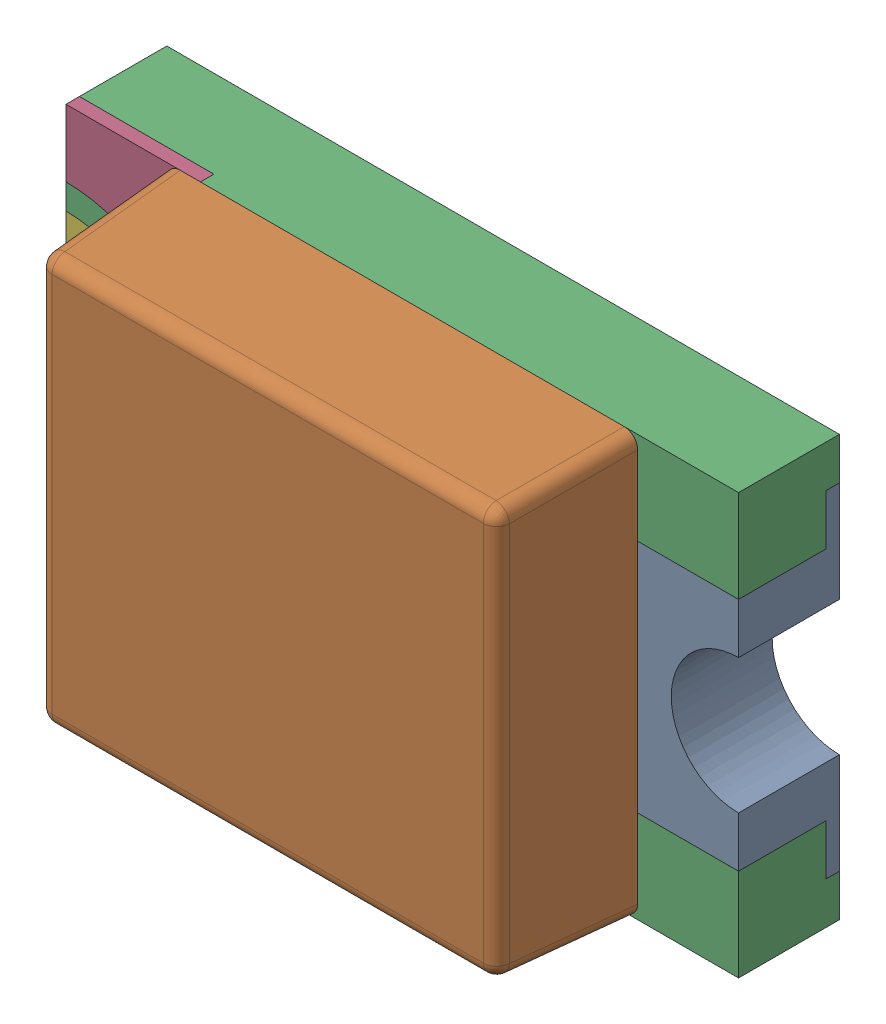
SolidWorks assembly D9, configuration Standard. Lengths in mm.
Overall size (2 1.25 0.7).
7 component instances, 5 part files, 0 mates.
Components (placement in the parent):
- WL-SMCW_0805_LED-1: WL-SMCW_0805_LED [Standard] at (12.1103 16.5697 -0.02) x (1 0 0) z (0 0 1) size (2 1.25 0.7)
  - base-1: base [Standard] at (0.8 0 0) x (-1 0 0) z (0 0 1) size (0.4 1 0.3)
  - cover-1: cover [Standard] at (0 0 0.3) size (1.4 1.25 0.4)
  - housing_3-1: housing_3 [Standard] at origin size (2 1.25 0.3)
  - marking-1: marking [Standard] at (-0.8 0.525 0.26) size (0.4 0.48 0.04)
  - marking-2: marking [Standard] at (-0.8 -0.525 0.3) x (1 0 0) z (0 0 -1) size (0.4 0.48 0.04)
  - base_2-1: base_2 [Standard] at (-0.8 0 0) size (0.4 1 0.3)
